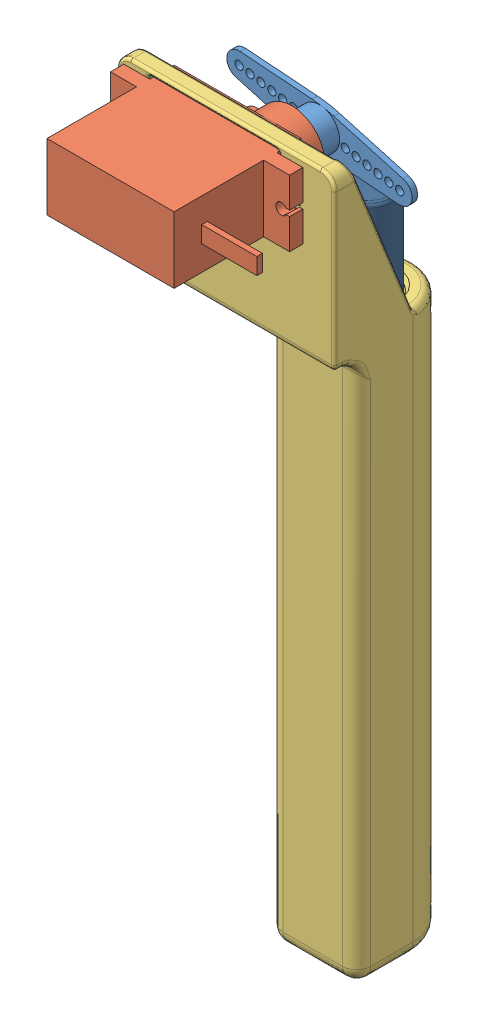
SolidWorks assembly PenHolder, configuration Default. Lengths in mm.
Overall size (63.5 135.18 40.74).
12 component instances, 10 part files, 12 mates.
Components (placement in the parent):
- Servo Lever-1: Servo Lever [Default] at (-8.47 71.374 -10.66) x (-0.174014 -0.984743 0) z (-0.984743 0.174014 0) size (7.3 5 34)
- SG90 Servo-1: SG90 Servo [Default] at (-13.97 71.374 -0.36) x (-1 0 0) z (0 -1 0) size (37.7 30.3 12)
- PenHolder-1: PenHolder [Default] at origin size (63.5 129.54 22.14)
- Assembly Ink Cartridge Pilot G2-1: Assembly Ink Cartridge Pilot G2 [Default] at (-23.3837 82.8066 -54.1169) x (1 0 0) z (0 -1 0) size (10.07 10.07 120.93)
  - Ink Container Tube-2: Ink Container Tube [Default] at (23.3837 43.9569 29.8776) x (-1 0 0) z (0 1 0) size (6.2 88 6)
  - Ink Container Back Plug-1: Ink Container Back Plug [Default] at (23.3837 43.9569 29.8776) x (1 0 0) z (0 1 0) size (6 4.9 6)
  - Pen Tip Holder-1: Pen Tip Holder [Default] at (23.3837 43.9569 117.8776) x (0.558829 -0.829283 0) z (0.829283 0.558829 0) size (6 18.11 6)
  - Pen Tip-1: Pen Tip [Default] at (23.3837 43.9569 135.6644) x (0.943336 0.33184 0) z (-0.33184 0.943336 0) size (2.59 15.69 2.63)
  - Roller Ball-2: Roller Ball [Default] at (23.3837 43.9569 138.8644) x (0.307657 -0.299861 -0.903012) z (0.951494 0.099481 0.29114) size (0.5 0.5 0.5)
  - Spring-2: Spring [Write] at (23.4744 43.9159 120.9776) x (0.558829 -0.829283 0) z (-0.829283 -0.558829 0) size (7.26 11.16 7.26)
  - Spring-3: Spring [Write] at (23.3837 43.9569 20.2276) x (1 0 0) z (0 -1 0) size (7.26 11.16 7.26)
- Spring Cap-1: Spring Cap [Default] at (0 19.729 -10.16) x (-1 0 0) z (0 0 -1) size (8.89 46.99 8.89)
Mates (geometry in assembly coordinates):
- Concentric1: concentric anti-aligned: cylinder of Servo Lever-1 through (-8.47 71.374 -5.66) axis (0 0 -1) radius 0.75; cylinder of SG90 Servo-1 through (-8.47 71.374 -4.66) axis (0 0 1) radius 6
- Coincident2: coordinate: point of PenHolder-1
- Concentric4: concentric anti-aligned: cylinder of PenHolder-1 through (0 -47.625 -10.16) axis (0 -1 0) radius 1.397; cylinder of Assembly Ink Cartridge Pilot G2-1/Ink Container Tube-2 through (0 -35.071 -10.16) axis (0 1 0) radius 3
- Distance2: distance = 0.254 mm anti-aligned: plane of Assembly Ink Cartridge Pilot G2-1/Pen Tip Holder-1 through (0 -47.371 -10.16) normal (0 -1 0); plane of PenHolder-1 through (0 -47.625 -10.16) normal (0 1 0)
- Coincident7: coincident anti-aligned: plane of Servo Lever-1 through (-8.47 71.374 -7.66) normal (0 0 1); plane of SG90 Servo-1 through (-13.97 71.374 -7.66) normal (0 0 -1)
- Parallel2: parallel aligned: plane of Assembly Ink Cartridge Pilot G2-1 through (-23.3837 82.8066 -54.1169) normal (0 0 1)
- Symmetric1: symmetric aligned: plane of Servo Lever-1 through (6.055 68.8073 -10.66) normal (0 0 -1); plane of Assembly Ink Cartridge Pilot G2-1/Ink Container Back Plug-1 through (6.055 68.8073 -9.66) normal (0 0 1); plane of Servo Lever-1 through (0 52.929 -10.16) normal (0 0 1)
- Parallel3: parallel anti-aligned: plane of SG90 Servo-1 through (-13.97 71.374 -0.36) normal (-1 0 0)
- Coincident8: coincident anti-aligned: plane of Assembly Ink Cartridge Pilot G2-1/Spring-3 through (0 64.179 -10.16) normal (0 1 0); plane of Spring Cap-1 through (-3.302 64.179 -10.16) normal (0 -1 0)
- Concentric5: concentric anti-aligned: cylinder of PenHolder-1 through (0 50.8 -10.16) axis (0 -1 0) radius 7.9375; cylinder of Spring Cap-1 through (0 64.179 -10.16) axis (0 1 0) radius 4.445
- Concentric6: concentric aligned: cylinder of SG90 Servo-1 through (-27.9984 71.374 6.44) axis (0 0 -1) radius 1; cylinder of PenHolder-1 through (-27.9984 71.374 4.0386) axis (0 0 -1) radius 0.635
- Parallel4: parallel anti-aligned: plane of Spring Cap-1 through (0 19.729 -10.16) normal (0 0 -1)
